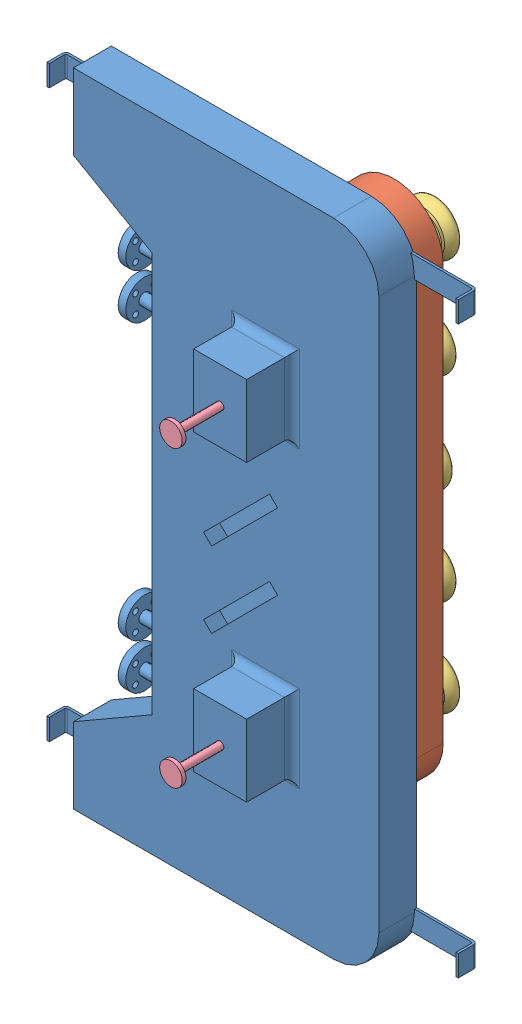
SolidWorks assembly Cap Assembly, configuration Default. Lengths in mm.
Overall size (690.28 1077.29 454.96).
30 component instances, 9 part files, 24 mates.
Components (placement in the parent):
- Top Cap-1: Top Cap [Default] at (0 0 3081.8977) size (690.28 1077.29 147.32)
- Plugs Fixer-2: Plugs Fixer [Default] at (327.3273 0 1939.3509) x (0 0 1) z (-1 0 0) size (76.2 861.39 164.5)
- Plug-1: Plug [Default] at (327.3273 0 2929.4977) x (-1 0 0) z (0 0 -1) size (98.84 98.84 202.97)
- Plug-2: Plug [Default] at (327.3273 164.5467 2935.8477) x (-1 0 0) z (0 0 -1) size (98.84 98.84 202.97)
- Plug-3: Plug [Default] at (-861.6126 1543.829 2942.1977) x (-0.219587 0.975593 0) z (0 0 -1) size (98.84 98.84 202.97)
- Plug-4: Plug [Default] at (327.3273 493.6401 2935.8477) x (-1 0 0) z (0 0 -1) size (98.84 98.84 202.97)
- Plug-5: Plug [Default] at (1603.584 1224.0286 2929.4977) x (-0.473539 -0.880773 0) z (0 0 -1) size (98.84 98.84 202.97)
- Damper Assembly-1: Damper Assembly [Default] at (0 0 3107.2977) x (-1 0 0) z (0 0 -1) size (38 38 377.82) (flexible)
  - Damper Rod-1: Damper Rod [Default] at (-301.9273 0 25.4) x (0 0 -1) z (1 0 0) size (377.82 38 38)
  - Damper Cylinder-1: Damper Cylinder [Default] at origin size (32.82 32.82 101.6)
  - O-Ring-1: O-Ring [Default] at (-492.1271 0 0) x (0 0 -1) z (1 0 0) size (1.27 26.37 26.37)
- Spacer-1: Spacer [Default] at (327.3273 0 3005.6977) size (70.92 70.92 13.97)
- Washer-1: Washer [Default] at (327.3273 0 3019.6677) size (68.38 68.38 1.59)
- Heavy Hex Flat Nut-1: Heavy Hex Flat Nut [Default] at (327.3273 0 3021.2552) size (70.92 61.42 23.81)
- Spacer-2: Spacer [Default] at (327.3273 164.5412 3005.6977) size (70.92 70.92 13.97)
- Spacer-3: Spacer [Default] at (327.3273 329.0824 3005.6977) size (70.92 70.92 13.97)
- Spacer-4: Spacer [Default] at (327.3273 493.6236 3005.6977) size (70.92 70.92 13.97)
- Spacer-5: Spacer [Default] at (327.3273 658.1648 3005.6977) size (70.92 70.92 13.97)
- Washer-3: Washer [Default] at (327.3273 164.5412 3019.6677) size (68.38 68.38 1.59)
- Washer-4: Washer [Default] at (327.3273 329.0824 3019.6677) size (68.38 68.38 1.59)
- Washer-5: Washer [Default] at (327.3273 493.6236 3019.6677) size (68.38 68.38 1.59)
- Washer-6: Washer [Default] at (327.3273 658.1648 3019.6677) size (68.38 68.38 1.59)
- Heavy Hex Flat Nut-2: Heavy Hex Flat Nut [Default] at (327.3273 164.5412 3021.2552) size (70.92 61.42 23.81)
- Heavy Hex Flat Nut-3: Heavy Hex Flat Nut [Default] at (327.3273 329.0824 3021.2552) size (70.92 61.42 23.81)
- Heavy Hex Flat Nut-4: Heavy Hex Flat Nut [Default] at (327.3273 493.6236 3021.2552) size (70.92 61.42 23.81)
- Heavy Hex Flat Nut-5: Heavy Hex Flat Nut [Default] at (327.3273 658.1648 3021.2552) size (70.92 61.42 23.81)
- Damper Assembly-2: Damper Assembly [Default] at (984.2542 3359.2148 3107.2977) x (1 0 0) z (0 0 -1) size (38 38 377.82)
  - Damper Rod-1: Damper Rod [Default] at (-301.9273 0 25.4) x (0 0 -1) z (1 0 0) size (377.82 38 38)
  - Damper Cylinder-1: Damper Cylinder [Default] at origin size (32.82 32.82 101.6)
  - O-Ring-1: O-Ring [Default] at (-492.1271 0 0) x (0 0 -1) z (1 0 0) size (1.27 26.37 26.37)
Mates (geometry in assembly coordinates):
- InPlace6: in place: plane of Plugs Fixer-2 through (492.1271 2028.051 2929.4977) normal (0 0 -1); plane of ? through (0 0 2929.4977) normal (0 0 -1); moOrthogonalPlaneRef_w of Plugs Fixer-2 through (492.1271 2028.051 2929.4977) normal (0 0 -1); unknown of ?; plane of Plugs Fixer-2 through (492.1271 2028.051 2929.4977) normal (0 0 -1); plane of ? through (0 0 2929.4977) normal (-1 0 0); plane of Plugs Fixer-2 through (492.1271 2028.051 2929.4977) normal (0 0 -1); unknown of Plug-1
- Coincident89: coincident aligned: plane of Plugs Fixer-2; plane of Plug-1
- Coincident90: coincident aligned: moOrthogonalPlaneRef_w of Plugs Fixer-2 through (327.3273 0 2929.4977) normal (0 1 0); plane of Plug-1
- Coincident91: coincident anti-aligned: moOrthogonalPlaneRef_w of Plugs Fixer-2 through (327.3273 0 2929.4977) normal (1 0 0); plane of Plug-1 through (327.3273 0 2929.4977) normal (-1 0 0)
- Concentric10: concentric aligned: cylinder of Plugs Fixer-2 through (492.1271 1515.0607 2929.4967) axis (0 0 1) radius 22.86; cylinder of Plug-2 through (492.1271 1515.0607 2774.9573) axis (0 0 1) radius 22.7584
- Distance30: distance = 6.35 mm aligned: plane of Plug-2 through (492.1271 2192.5977 3057.7677) normal (0 0 1); plane of Plug-1 through (492.1271 2028.051 3051.4177) normal (0 0 1)
- Concentric11: concentric aligned: cylinder of Plugs Fixer-2 through (492.1271 1679.6074 2929.4967) axis (0 0 1) radius 22.86; cylinder of Plug-3 through (492.1271 1679.6074 2781.3073) axis (0 0 1) radius 22.7584
- Distance31: distance = 6.35 mm aligned: plane of Plug-3 through (1153.1274 1828.386 3064.1177) normal (0 0 1); plane of Plug-2 through (492.1271 2192.5977 3057.7677) normal (0 0 1)
- Concentric12: concentric aligned: cylinder of Plugs Fixer-2 through (492.1271 1844.1541 2929.4967) axis (0 0 1) radius 22.86; cylinder of Plug-4 through (492.1271 1844.1541 2774.9573) axis (0 0 1) radius 22.7584
- Coincident94: coincident aligned: plane of Plug-2 through (492.1271 2192.5977 3057.7677) normal (0 0 1); plane of Plug-4 through (492.1271 2521.6911 3057.7677) normal (0 0 1)
- Concentric131: concentric aligned: cylinder of Plugs Fixer-2 through (492.1271 2008.7008 2929.4967) axis (0 0 1) radius 22.86; cylinder of Plug-5 through (492.1271 2008.7008 2768.6073) axis (0 0 1) radius 22.7584
- Coincident951: coincident aligned: plane of Plug-1 through (492.1271 2028.051 3051.4177) normal (0 0 1); plane of Plug-5 through (-104.6291 2329.541 3051.4177) normal (0 0 1)
- InPlace9: in place: plane of Plugs Fixer-2 through (492.1271 2028.051 3005.6977) normal (0 0 1); plane of ? through (0 0 3005.6977) normal (0 0 1); plane of Plugs Fixer-2 through (492.1271 2028.051 3005.6977) normal (0 0 1); plane of ? through (0 0 3005.6977) normal (0 1 0); plane of Plugs Fixer-2 through (492.1271 2028.051 3005.6977) normal (0 0 1); plane of ? through (0 0 3005.6977) normal (1 0 0); plane of Plugs Fixer-2 through (492.1271 2028.051 3005.6977) normal (0 0 1); unknown of Spacer-1
- Coincident102: coincident aligned: plane of Plugs Fixer-2; plane of Spacer-1
- Coincident103: coincident aligned: moOrthogonalPlaneRef_w of Plugs Fixer-2 through (327.3273 0 3005.6977) normal (0 1 0); plane of Spacer-1 through (327.3273 0 3005.6977) normal (0 1 0)
- Coincident104: coincident anti-aligned: moOrthogonalPlaneRef_w of Plugs Fixer-2 through (327.3273 0 3005.6977) normal (-1 0 0); plane of Spacer-1 through (327.3273 0 3005.6977) normal (1 0 0)
- InPlace10: in place: plane of Spacer-1 through (492.1271 1350.514 3024.7477) normal (0 0 1); plane of ? through (0 0 3024.7477) normal (0 0 1); plane of Spacer-1 through (492.1271 1350.514 3024.7477) normal (0 0 1); plane of ? through (0 0 3024.7477) normal (0 1 0); plane of Spacer-1 through (492.1271 1350.514 3024.7477) normal (0 0 1); plane of ? through (0 0 3024.7477) normal (1 0 0); plane of Spacer-1 through (492.1271 1350.514 3019.6677) normal (0 0 1); unknown of Washer-1
- Coincident105: coincident aligned: plane of Spacer-1; plane of Washer-1
- Coincident106: coincident aligned: moOrthogonalPlaneRef_w of Spacer-1 through (327.3273 0 3019.6677) normal (0 1 0); plane of Washer-1 through (327.3273 0 3019.6677) normal (0 1 0)
- Coincident107: coincident anti-aligned: moOrthogonalPlaneRef_w of Spacer-1 through (327.3273 0 3019.6677) normal (-1 0 0); plane of Washer-1 through (327.3273 0 3019.6677) normal (1 0 0)
- InPlace11: in place: plane of Washer-1 through (492.1271 1350.514 3021.2552) normal (0 0 1); plane of ? through (0 0 3021.2552) normal (0 0 1); plane of Washer-1 through (492.1271 1350.514 3021.2552) normal (0 0 1); plane of ? through (0 0 3021.2552) normal (0 1 0); plane of Washer-1 through (492.1271 1350.514 3021.2552) normal (0 0 1); plane of ? through (0 0 3021.2552) normal (1 0 0); plane of Washer-1 through (492.1271 1350.514 3021.2552) normal (0 0 1); unknown of Heavy Hex Flat Nut-1
- Coincident108: coincident aligned: plane of Washer-1; plane of Heavy Hex Flat Nut-1
- Coincident109: coincident aligned: moOrthogonalPlaneRef_w of Washer-1 through (327.3273 0 3021.2552) normal (0 1 0); plane of Heavy Hex Flat Nut-1 through (327.3273 0 3021.2552) normal (0 1 0)
- Coincident110: coincident anti-aligned: moOrthogonalPlaneRef_w of Washer-1 through (327.3273 0 3021.2552) normal (-1 0 0); plane of Heavy Hex Flat Nut-1 through (327.3273 0 3021.2552) normal (1 0 0)
